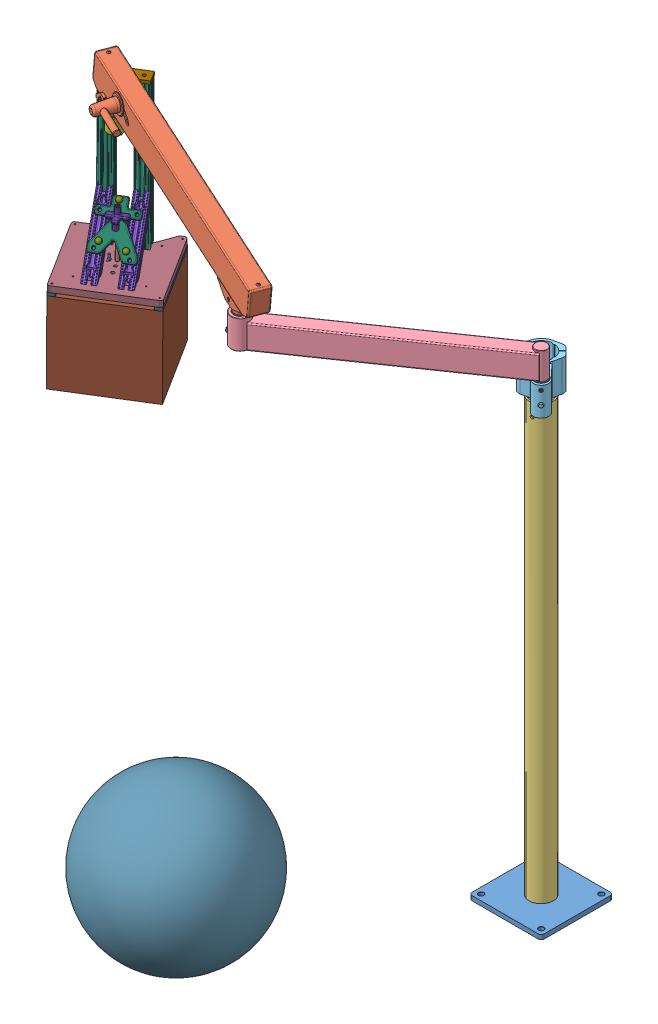
SolidWorks assembly Assem1, configuration Default. Lengths in mm.
Overall size (1056.1 1237.71 1022.3).
27 component instances, 20 part files, 58 mates.
Components (placement in the parent):
- tableMount-1: tableMount [Default] at origin size (152.4 70.23 152.4)
- heightAdjustArm-1: heightAdjustArm [Default] at (-302.796 994.7266 358.8585) x (-0.350834 0 0.936438) z (-0.936438 0 -0.350834) size (93.56 236.21 568.85)
- pole-1: pole [Default] at (11.9378 -91.6107 8.4845) x (0.977048 0 -0.213019) z (0.213019 0 0.977048) size (50.8 914.4 50.8)
- rigidarm-1: rigidarm [Default] at (-85.8705 941.6654 201.5266) x (0.567993 0 0.823033) z (-0.823033 0 0.567993) size (38.1 127.38 493.87)
- poleMount-2: poleMount [Default] at (111.5423 862.7925 -247.2792) x (0.71 0 -0.704202) z (0.704202 0 0.71) size (74.61 66.55 119.23)
- 8020_1ft-1: 8020_1ft [47065T411] at (-798.3579 907.5321 116.7584) x (0.533661 -0.007014 0.845669) z (0.008246 0.999961 0.00309) size (25.4 25.4 304.8)
- 8020_1ft-2: 8020_1ft [47065T411] at (-750.0286 907.2278 86.2575) x (0.845658 -0.005325 -0.533699) z (-0.008246 -0.999961 -0.00309) size (25.4 25.4 304.8)
- EndEffector-1: EndEffector [Default] at (-779.0664 1045.3947 50.0464) x (0.845658 -0.005325 -0.533699) z (0.533661 -0.007014 0.845669) size (76.2 76.2 100.61)
- 8020_6inCorner-1: 8020_6inCorner [47065T186] at (-720.1754 799.3293 134.6371) x (0.845658 -0.005325 -0.533699) z (0.371525 -0.712039 0.595794) size (25.4 25.56 152.4)
- 8020_6inCorner-2: 8020_6inCorner [47065T186] at (-768.5047 799.6336 165.138) x (0.845658 -0.005325 -0.533699) z (0.371525 -0.712039 0.595794) size (25.4 25.56 152.4)
- 8020_cap-1: 8020_cap [Default] at (-801.0635 1059.9047 134.7472) x (0.845658 -0.005325 -0.533699) z (0.533661 -0.007014 0.845669) size (82.55 6.35 25.4)
- OmniTopPlate-1: OmniTopPlate [Default] at (-717.9494 735.5157 25.769) x (-0.845658 0.005325 0.533699) z (-0.533661 0.007014 -0.845669) size (177.8 6.53 168.28)
- omnimagnet-1: omnimagnet [Default] at (-717.9494 735.5157 25.769) x (0.533661 -0.007014 0.845669) z (-0.008246 -0.999961 -0.00309) size (168.28 177.8 171.45)
- 8020Fastener-9: 8020Fastener [47065T226] at (-789.9413 1050.2973 131.6253) x (-0.845658 0.005325 0.533699) z (0.008246 0.999961 0.00309) size (11.1 18.3 16.15)
- Mount_halfInch-1: Mount_halfInch [Default] at (-868.2535 742.99 120.6808) x (0.533661 -0.007014 0.845669) z (-0.845658 0.005325 0.533699) size (168.28 12.7 177.8)
- BoundingSphere-1: BoundingSphere [Default] at (21.2768 351.7313 789.4808) size (330.2 330.2 330.2)
- omniRigBody-1: omniRigBody [Default] at (-745.9258 820.7643 147.1625) x (0.845658 -0.005325 -0.533699) z (0.371525 -0.712039 0.595794) size (78.64 8.89 100.95)
- NDI_fiducial-1: NDI_fiducial [Default] at (-756.6744 854.1348 129.7982) x (0.891593 -0.45091 -0.041744) z (-0.24131 -0.551097 0.798788) size (11.5 14.52 11.5)
- NDI_fiducial-2: NDI_fiducial [Default] at (-709.0271 799.7113 163.046) x (0.891593 -0.45091 -0.041744) z (-0.24131 -0.551097 0.798788) size (11.5 14.52 11.5)
- NDI_fiducial-3: NDI_fiducial [Default] at (-749.8596 807.2234 180.3281) x (0.898299 -0.434519 -0.065202) z (-0.215003 -0.564111 0.797216) size (11.5 14.52 11.5)
- centerPiece-1: centerPiece [Default] at (-747.5113 822.2313 144.6356) x (0.533661 -0.007014 0.845669) z (-0.845658 0.005325 0.533699) size (38.8 34.29 38.8)
- ballbearing-1: ballbearing [57155K351] at (-736.76 823.5527 137.8619) x (0.999937 -0.008269 0.007574) z (-0.008246 -0.999961 -0.00309) size (7.94 7.94 2.78)
- ballbearing-2: ballbearing [57155K351] at (-754.2774 823.7094 133.8999) x (0.999852 -0.008292 0.015068) z (-0.008246 -0.999961 -0.00309) size (7.94 7.94 2.78)
- ballbearing-3: ballbearing [57155K351] at (-740.7224 823.5313 155.3799) x (0.999881 -0.008286 0.013011) z (-0.008246 -0.999961 -0.00309) size (7.94 7.94 2.78)
- ballbearing-4: ballbearing [57155K351] at (-758.2397 823.688 151.4178) x (0.999927 -0.008273 0.008782) z (-0.008246 -0.999961 -0.00309) size (7.94 7.94 2.78)
- flathead-1: flathead [Default] at (-758.7668 759.7734 151.2204) x (0.99989 -0.008284 0.012302) z (-0.012327 -0.002988 0.99992) size (3.96 11.44 9.37)
- rod-2: rod [Default] at (-748.0692 754.5837 144.4266) x (0.999923 -0.008275 0.009288) z (0.008246 0.999961 0.00309) size (6.35 6.35 100)
Mates (geometry in assembly coordinates):
- Concentric1: concentric anti-aligned: cylinder of tableMount-1 through (11.9378 -62.6547 8.4845) axis (0 1 0) radius 11.1125; cylinder of pole-1 through (11.9378 822.7893 8.4845) axis (0 -1 0) radius 25.4
- Coincident1: coincident anti-aligned: plane of tableMount-1 through (88.1378 -91.6107 -67.7155) normal (0 1 0); plane of pole-1 through (11.9378 -91.6107 8.4845) normal (0 -1 0)
- Concentric5: concentric aligned: cylinder of pole-1 through (11.9378 822.7893 8.4845) axis (0 -1 0) radius 25.4; cylinder of poleMount-2 through (11.9378 902.6426 8.4845) axis (0 -1 0) radius 26.3525
- Coincident5: coincident aligned: plane of 8020_1ft-1 through (-808.4829 1060.0213 116.8251) normal (0.008246 0.999961 0.00309); plane of 8020_1ft-2 through (-759.2196 1059.722 82.1952) normal (0.008246 0.999961 0.00309)
- Coincident8: coincident aligned: plane of 8020_1ft-1 through (-795.8023 1059.9644 101.3922) normal (-0.533661 0.007014 -0.845669); plane of 8020_1ft-2 through (-752.7071 754.889 71.6667) normal (-0.533661 0.007014 -0.845669)
- Parallel1: parallel aligned: plane of 8020_1ft-2 through (-759.2196 1059.722 82.1952) normal (0.008246 0.999961 0.00309); plane of EndEffector-1 through (-816.656 1060.1189 107.0444) normal (0.008246 0.999961 0.00309)
- Coincident11: coincident anti-aligned: plane of 8020_1ft-1 through (-798.4001 1059.888 133.0663) normal (0.533661 -0.007014 0.845669); plane of 8020_6inCorner-2 through (-802.9846 826.956 134.0275) normal (-0.533661 0.007014 -0.845669)
- Coincident12: coincident aligned: plane of 8020_1ft-1 through (-810.9963 755.2331 115.8834) normal (-0.008246 -0.999961 -0.00309); plane of 8020_6inCorner-2 through (-765.2375 754.6127 194.5603) normal (-0.008246 -0.999961 -0.00309)
- Coincident13: coincident aligned: plane of 8020_1ft-1 through (-804.4613 1059.9494 129.3629) normal (-0.845658 0.005325 0.533699); plane of 8020_6inCorner-2 through (-747.2748 752.1494 223.0472) normal (-0.845658 0.005325 0.533699)
- Coincident14: coincident aligned: plane of 8020_1ft-2 through (-756.9285 754.8343 100.6411) normal (-0.845658 0.005325 0.533699); plane of 8020_6inCorner-1 through (-698.9455 751.8451 192.5464) normal (-0.845658 0.005325 0.533699)
- Coincident15: coincident anti-aligned: plane of 8020_1ft-2 through (-749.8634 754.7783 99.9066) normal (0.533661 -0.007014 0.845669); plane of 8020_6inCorner-1 through (-754.6552 826.6517 103.5266) normal (-0.533661 0.007014 -0.845669)
- Coincident16: coincident aligned: plane of 8020_1ft-2 through (-761.733 754.9338 81.2535) normal (-0.008246 -0.999961 -0.00309); plane of 8020_6inCorner-1 through (-716.9082 754.3084 164.0594) normal (-0.008246 -0.999961 -0.00309)
- Coincident32: coincident anti-aligned: plane of 8020_1ft-1 through (-808.4829 1060.0213 116.8251) normal (0.008246 0.999961 0.00309); plane of 8020_cap-1 through (-801.0635 1059.9047 134.7472) normal (-0.008246 -0.999961 -0.00309)
- Concentric23: concentric aligned: cylinder of 8020_1ft-1 through (-797.1012 1059.9262 117.2292) axis (-0.008246 -0.999961 -0.00309) radius 2.6035; cylinder of 8020_cap-1 through (-797.0488 1066.2759 117.2488) axis (-0.008246 -0.999961 -0.00309) radius 3.302
- Concentric24: concentric anti-aligned: cylinder of 8020_1ft-2 through (-751.2853 754.8337 85.7867) axis (0.008246 0.999961 0.00309) radius 2.6035; cylinder of 8020_cap-1 through (-748.7195 1065.9716 86.748) axis (-0.008246 -0.999961 -0.00309) radius 3.302
- Coincident33: coincident anti-aligned: plane of EndEffector-1 through (-816.656 1060.1189 107.0444) normal (0.008246 0.999961 0.00309); plane of 8020_cap-1 through (-801.0635 1059.9047 134.7472) normal (-0.008246 -0.999961 -0.00309)
- Coincident48: coincident anti-aligned: line of OmniTopPlate-1 through (-628.1475 734.3354 168.074) axis (-0.533661 0.007014 -0.845669); line of omnimagnet-1 through (-717.9494 735.5157 25.769) axis (0.533661 -0.007014 0.845669)
- Coincident49: coincident aligned: plane of OmniTopPlate-1 through (-717.8955 742.0432 25.7892) normal (-0.533661 0.007014 -0.845669); plane of omnimagnet-1 through (-719.3632 564.0723 25.2393) normal (-0.533661 0.007014 -0.845669)
- Coincident50: coincident anti-aligned: plane of OmniTopPlate-1 through (-748.2274 735.3989 144.3673) normal (-0.008246 -0.999961 -0.00309); plane of omnimagnet-1 through (-717.9494 735.5157 25.769) normal (0.008246 0.999961 0.00309)
- Coincident53: coincident anti-aligned: plane of 8020_1ft-2 through (-766.1392 754.9736 80.1437) normal (-0.533661 0.007014 -0.845669); plane of EndEffector-1 through (-781.3619 1021.773 91.9628) normal (0.533661 -0.007014 0.845669)
- Concentric47: concentric anti-aligned: cylinder of 8020_1ft-1 through (-797.4652 1059.8939 128.6484) axis (-0.008246 -0.999961 -0.00309) radius 1.0274; cylinder of 8020Fastener-9 through (-797.6312 1039.7697 128.5862) axis (0.008246 0.999961 0.00309) radius 0.25
- Concentric48: concentric aligned: cylinder of EndEffector-1 through (-805.2909 1050.499 107.3015) axis (0.533661 -0.007014 0.845669) radius 3.5719; cylinder of 8020Fastener-9 through (-789.9413 1050.2973 131.6253) axis (0.533661 -0.007014 0.845669) radius 5.5499
- Coincident54: coincident anti-aligned: plane of rigidarm-1 through (67.0792 839.2061 47.9283) normal (0 1 0); plane of poleMount-2 through (60.5685 839.2061 80.0408) normal (0 -1 0)
- Concentric50: concentric anti-aligned: cylinder of rigidarm-1 through (58.4247 901.6393 55.3361) axis (0 -1 0) radius 11.1023; cylinder of poleMount-2 through (58.4247 868.1621 55.3361) axis (0 1 0) radius 11.1125
- Concentric52: concentric aligned: cylinder of heightAdjustArm-1 through (-739.6285 1109.6988 157.2131) axis (0.008246 0.999961 0.00309) radius 11.0998; cylinder of EndEffector-1 through (-740.4868 1005.6137 156.8915) axis (0.008246 0.999961 0.00309) radius 11.1125
- Coincident55: coincident anti-aligned: plane of heightAdjustArm-1 through (-729.4594 1005.8949 159.7616) normal (0.008246 0.999961 0.00309); plane of EndEffector-1 through (-740.4837 1005.9947 156.8927) normal (-0.008246 -0.999961 -0.00309)
- Concentric54: concentric aligned: cylinder of heightAdjustArm-1 through (-317.9288 1057.5953 315.066) axis (0 1 0) radius 11.0998; cylinder of rigidarm-1 through (-317.9287 932.1193 315.066) axis (0 1 0) radius 11.1125
- Coincident56: coincident anti-aligned: plane of heightAdjustArm-1 through (-320.822 903.1633 326.0843) normal (0 1 0); plane of rigidarm-1 through (-317.9287 903.1633 315.066) normal (0 -1 0)
- Coincident66: coincident aligned: plane of OmniTopPlate-1 through (-868.2535 742.99 120.6808) normal (-0.533661 0.007014 -0.845669); plane of Mount_halfInch-1 through (-717.7908 754.7427 25.8284) normal (-0.533661 0.007014 -0.845669)
- Coincident67: coincident anti-aligned: plane of OmniTopPlate-1 through (-748.1736 741.9265 144.3875) normal (0.008246 0.999961 0.00309); plane of Mount_halfInch-1 through (-868.2535 742.99 120.6808) normal (-0.008246 -0.999961 -0.00309)
- Concentric58: concentric aligned: cylinder of 8020_1ft-1 through (-797.1012 1059.9262 117.2292) axis (-0.008246 -0.999961 -0.00309) radius 2.6035; cylinder of Mount_halfInch-1 through (-799.6146 755.138 116.2875) axis (-0.008246 -0.999961 -0.00309) radius 2.413
- Coincident68: coincident aligned: plane of OmniTopPlate-1 through (-634.8711 740.9521 157.3541) normal (0.845658 -0.005325 -0.533699); plane of Mount_halfInch-1 through (-717.7908 754.7427 25.8284) normal (0.845658 -0.005325 -0.533699)
- Coincident69: coincident aligned: plane of OmniTopPlate-1 through (-628.0936 740.863 168.0941) normal (0.533661 -0.007014 0.845669); plane of Mount_halfInch-1 through (-627.9889 753.5625 168.1334) normal (0.533661 -0.007014 0.845669)
- Concentric59: concentric anti-aligned: cylinder of 8020_1ft-2 through (-751.2853 754.8337 85.7867) axis (0.008246 0.999961 0.00309) radius 2.6035; cylinder of Mount_halfInch-1 through (-751.2853 754.8337 85.7867) axis (-0.008246 -0.999961 -0.00309) radius 2.413
- Coincident70: coincident anti-aligned: plane of 8020_6inCorner-1 through (-716.9082 754.3084 164.0594) normal (-0.008246 -0.999961 -0.00309); plane of Mount_halfInch-1 through (-868.1488 755.6895 120.72) normal (0.008246 0.999961 0.00309)
- Parallel2: parallel anti-aligned: plane of 8020_6inCorner-2 through (-740.6837 754.3269 221.5395) normal (0.383187 0.70212 0.600163); plane of omniRigBody-1 through (-745.9258 820.7643 147.1625) normal (-0.383187 -0.70212 -0.600163)
- Parallel3: parallel aligned: plane of 8020_6inCorner-1 through (-678.6986 749.4509 177.0595) normal (0.845658 -0.005325 -0.533699); plane of omniRigBody-1 through (-722.2911 846.7078 116.5343) normal (0.845658 -0.005325 -0.533699)
- Coincident74: coincident anti-aligned: plane of 8020_6inCorner-2 through (-727.2517 754.2424 213.0625) normal (0.383187 0.70212 0.600163); plane of omniRigBody-1 through (-745.9258 820.7643 147.1625) normal (-0.383187 -0.70212 -0.600163)
- Concentric60: concentric aligned: cylinder of omniRigBody-1 through (-749.8596 807.2234 180.3281) axis (-0.383187 -0.70212 -0.600163) radius 1.0287; cylinder of NDI_fiducial-3 through (-749.8596 807.2234 180.3281) axis (-0.383187 -0.70212 -0.600163) radius 2.795
- Coincident75: coincident anti-aligned: plane of omniRigBody-1 through (-742.5193 827.0061 152.498) normal (0.383187 0.70212 0.600163); plane of NDI_fiducial-3 through (-749.8596 807.2234 180.3281) normal (-0.383187 -0.70212 -0.600163)
- Concentric61: concentric aligned: cylinder of omniRigBody-1 through (-709.0271 799.7113 163.046) axis (-0.383187 -0.70212 -0.600163) radius 1.0287; cylinder of NDI_fiducial-2 through (-709.0271 799.7113 163.046) axis (-0.383187 -0.70212 -0.600163) radius 2.795
- Coincident76: coincident anti-aligned: plane of omniRigBody-1 through (-742.5193 827.0061 152.498) normal (0.383187 0.70212 0.600163); plane of NDI_fiducial-2 through (-709.0271 799.7113 163.046) normal (-0.383187 -0.70212 -0.600163)
- Concentric62: concentric aligned: cylinder of omniRigBody-1 through (-756.6744 854.1348 129.7982) axis (-0.383187 -0.70212 -0.600163) radius 1.0287; cylinder of NDI_fiducial-1 through (-756.6744 854.1348 129.7982) axis (-0.383187 -0.70212 -0.600163) radius 2.795
- Coincident77: coincident anti-aligned: plane of omniRigBody-1 through (-742.5193 827.0061 152.498) normal (0.383187 0.70212 0.600163); plane of NDI_fiducial-1 through (-756.6744 854.1348 129.7982) normal (-0.383187 -0.70212 -0.600163)
- Concentric65: concentric aligned: cylinder of Mount_halfInch-1 through (-758.8087 754.6936 151.2047) axis (-0.008246 -0.999961 -0.00309) radius 3.048; cylinder of centerPiece-1 through (-758.1465 834.9985 151.4528) axis (-0.008246 -0.999961 -0.00309) radius 3.9688
- Concentric66: concentric aligned: cylinder of Mount_halfInch-1 through (-737.329 754.5584 137.6487) axis (-0.008246 -0.999961 -0.00309) radius 3.048; cylinder of centerPiece-1 through (-736.6668 834.8632 137.8968) axis (-0.008246 -0.999961 -0.00309) radius 3.9688
- Concentric68: concentric anti-aligned: cylinder of omniRigBody-1 through (-747.5375 819.0567 144.6258) axis (0.008246 0.999961 0.00309) radius 3.175; cylinder of centerPiece-1 through (-747.2286 856.52 144.7415) axis (-0.008246 -0.999961 -0.00309) radius 3.175
- Concentric69: concentric aligned: cylinder of centerPiece-1 through (-740.6291 834.8418 155.4148) axis (-0.008246 -0.999961 -0.00309) radius 3.9688; cylinder of ballbearing-3 through (-740.7338 822.1423 155.3756) axis (-0.008246 -0.999961 -0.00309) radius 3.9688
- Concentric70: concentric aligned: cylinder of centerPiece-1 through (-754.1841 835.0199 133.9348) axis (-0.008246 -0.999961 -0.00309) radius 3.9688; cylinder of ballbearing-2 through (-754.2888 822.3204 133.8956) axis (-0.008246 -0.999961 -0.00309) radius 3.9688
- Concentric71: concentric aligned: cylinder of centerPiece-1 through (-736.6668 834.8632 137.8968) axis (-0.008246 -0.999961 -0.00309) radius 3.9688; cylinder of ballbearing-1 through (-736.7715 822.1637 137.8576) axis (-0.008246 -0.999961 -0.00309) radius 3.9688
- Concentric72: concentric aligned: cylinder of centerPiece-1 through (-758.1465 834.9985 151.4528) axis (-0.008246 -0.999961 -0.00309) radius 3.9688; cylinder of ballbearing-4 through (-758.2512 822.299 151.4135) axis (-0.008246 -0.999961 -0.00309) radius 3.9688
- Coincident78: coincident aligned: plane of ballbearing-2 through (-754.3237 825.0871 137.7335) normal (0.008246 0.999961 0.00309); plane of ballbearing-3 through (-740.7609 824.9089 159.2136) normal (0.008246 0.999961 0.00309)
- Coincident79: coincident aligned: plane of ballbearing-1 through (-736.7777 824.9301 141.6959) normal (0.008246 0.999961 0.00309); plane of ballbearing-3 through (-740.7609 824.9089 159.2136) normal (0.008246 0.999961 0.00309)
- Coincident80: coincident aligned: plane of ballbearing-2 through (-754.3237 825.0871 137.7335) normal (0.008246 0.999961 0.00309); plane of ballbearing-4 through (-758.262 825.0654 155.2518) normal (0.008246 0.999961 0.00309)
- Coincident81: coincident aligned: plane of centerPiece-1 through (-758.2512 822.299 151.4135) normal (-0.008246 -0.999961 -0.00309); plane of ballbearing-4 through (-758.2849 822.2874 155.2432) normal (-0.008246 -0.999961 -0.00309)
- Concentric73: concentric aligned: cylinder of ballbearing-4 through (-758.2512 822.299 151.4135) axis (-0.008246 -0.999961 -0.00309) radius 1.9844; cylinder of flathead-1 through (-758.7145 766.1232 151.24) axis (-0.008246 -0.999961 -0.00309) radius 1.9304
- Coincident82: coincident anti-aligned: plane of Mount_halfInch-1 through (-868.1488 755.6895 120.72) normal (0.008246 0.999961 0.00309); plane of flathead-1 through (-758.8557 754.6822 155.0144) normal (-0.008246 -0.999961 -0.00309)
- Concentric75: concentric anti-aligned: cylinder of omniRigBody-1 through (-747.5375 819.0567 144.6258) axis (0.008246 0.999961 0.00309) radius 3.175; cylinder of rod-2 through (-747.2446 854.5798 144.7355) axis (-0.008246 -0.999961 -0.00309) radius 3.175
